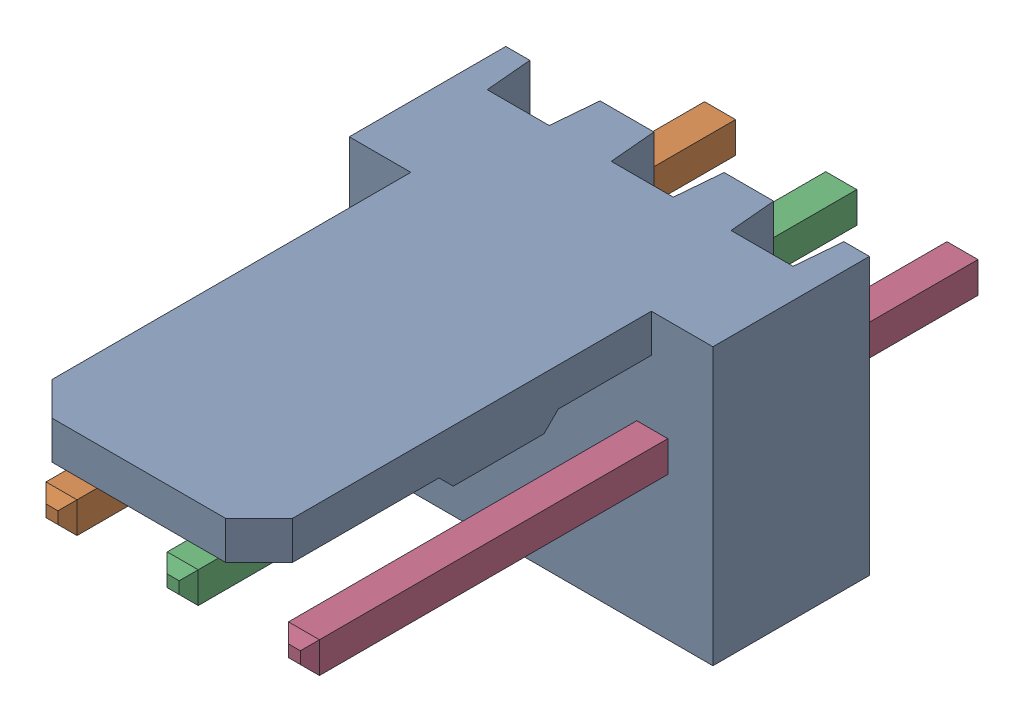
SolidWorks assembly Molex PCB 3 pin v2 v6_4, configuration Default. Lengths in mm.
Overall size (7.62 5.79 14.92).
4 component instances, 2 part files, 0 mates.
Components (placement in the parent):
- BASE9710016_2-1: BASE9710016_2 [Default] at (2.54 2.895 -8.22) size (7.62 5.79 11.5)
- PINO9710016_2-1: PINO9710016_2 [Default] at (1.27 3.325 -0.72) size (0.65 0.65 14.2)
- PINO9710016_2-2: PINO9710016_2 [Default] at (3.81 3.325 -0.72) size (0.65 0.65 14.2)
- PINO9710016_2-3: PINO9710016_2 [Default] at (6.35 3.325 -0.72) size (0.65 0.65 14.2)
